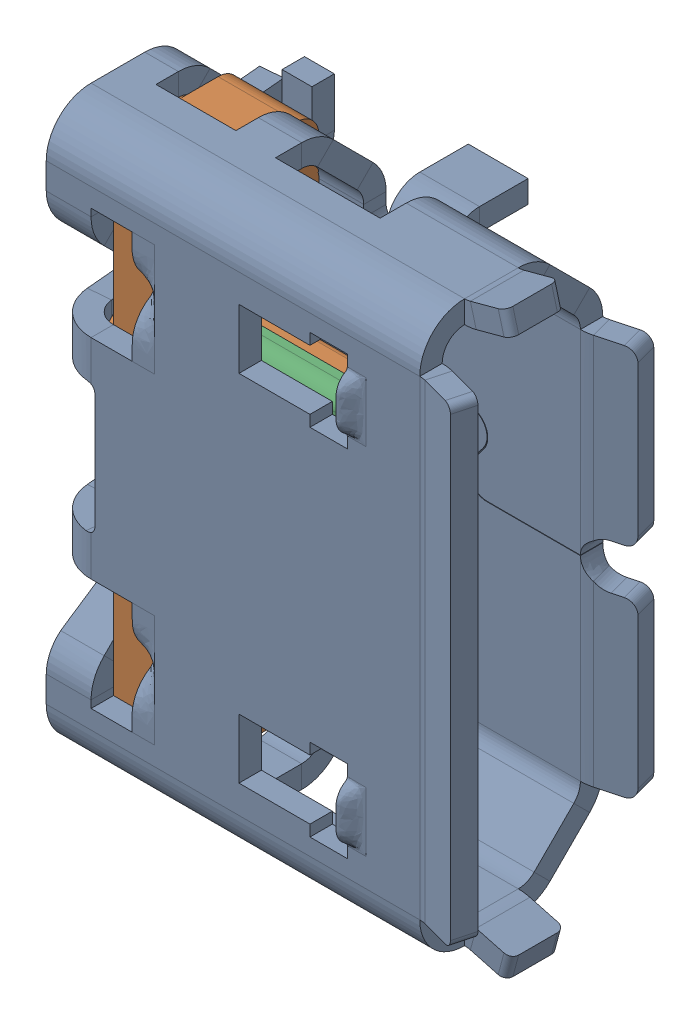
SolidWorks assembly micro_usb_connector v17.stp, configuration Default. Lengths in mm.
Overall size (5.84 7.77 3.4).
8 component instances, 4 part files, 0 mates.
Components (placement in the parent):
- shield.stp-1: shield.stp [Default] at origin size (5.84 7.77 3.4)
- socket_housing.stp-1: socket_housing.stp [Default] at origin size (4.25 6.85 2.15)
- socket_plate.stp-1: socket_plate.stp [Default] at origin size (3.38 6.8 0.31)
- terminal.stp-1: terminal.stp [Default] at origin size (3.22 0.35 1.72)
- terminal.stp-2: terminal.stp [Default] at (0 -1.3 0) size (3.22 0.35 1.72)
- terminal.stp-3: terminal.stp [Default] at (0 -0.65 0) size (3.22 0.35 1.72)
- terminal.stp-4: terminal.stp [Default] at (0 0.65 0) size (3.22 0.35 1.72)
- terminal.stp-5: terminal.stp [Default] at (0 1.3 0) size (3.22 0.35 1.72)
